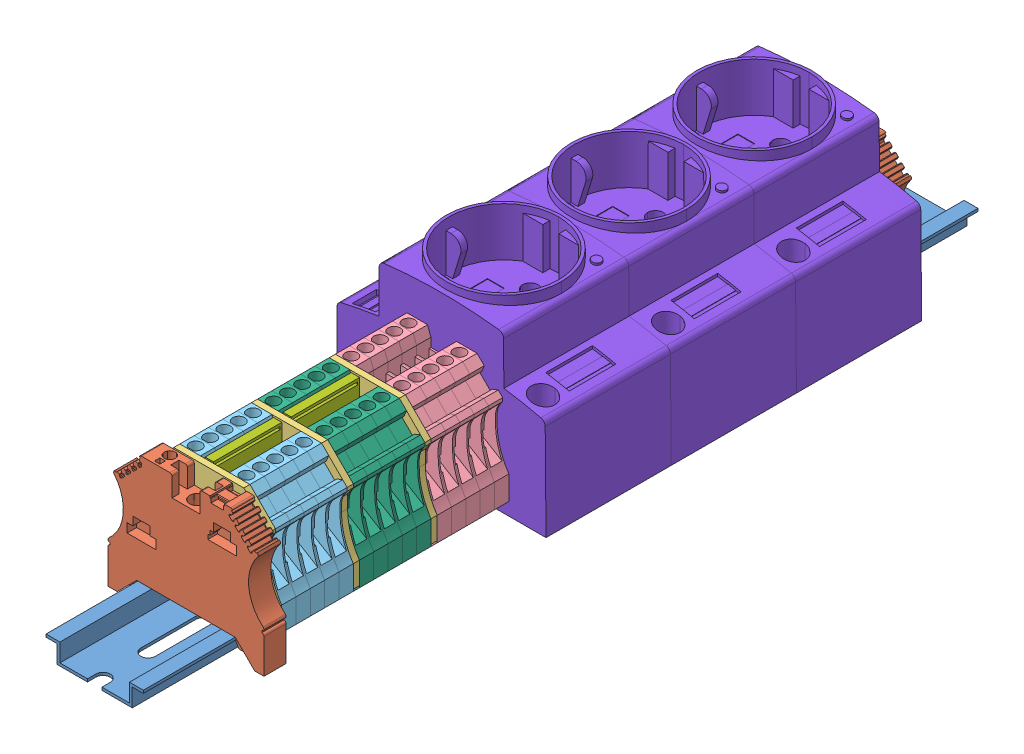
SolidWorks assembly 5xLNPE_Schuko, configuration Standard. Lengths in mm.
Overall size (75.48 67.56 300).
26 component instances, 8 part files, 78 mates.
Components (placement in the parent):
- Hutschiene-1: Hutschiene [300] at (-17.5 -7.5 -300) size (35 7.5 300)
- WEW_35_2-1: WEW_35_2 [Standard] at (-45.75 -7 -267.85) x (0 0 1) z (0 1 0) size (8 56.1 46.5)
- WEW_35_2-2: WEW_35_2 [Standard] at (10.35 -7 -33) x (0 0 -1) z (0 1 0) size (8 56.1 46.5)
- D_UT_2.5_10-1: D_UT_2.5_10 [Standard] at (-46.4297 58.45 -43.2) size (47 39.8 2.2)
- D_UT_2.5_10-2: D_UT_2.5_10 [Standard] at (-46.4297 58.45 -71.15) size (47 39.8 2.2)
- D_UT_2.5_10-3: D_UT_2.5_10 [Standard] at (-46.4297 58.45 -99.1) size (47 39.8 2.2)
- UT_2.5_PE-1: UT_2.5_PE [Standard] at (-48.6989 10.6178 -99.1) x (0.992546 -0.121869 0) z (0 0 1) size (49.27 50.96 5.15)
- UT_2.5_PE-2: UT_2.5_PE [Standard] at (-48.6989 10.6178 -104.25) x (0.992546 -0.121869 0) z (0 0 1) size (49.27 50.96 5.15)
- UT_2.5_PE-3: UT_2.5_PE [Standard] at (-48.6989 10.6178 -109.4) x (0.992546 -0.121869 0) z (0 0 1) size (49.27 50.96 5.15)
- UT_2.5_PE-4: UT_2.5_PE [Standard] at (-48.6989 10.6178 -114.55) x (0.992546 -0.121869 0) z (0 0 1) size (49.27 50.96 5.15)
- UT_2.5_PE-5: UT_2.5_PE [Standard] at (-48.6989 10.6178 -119.7) x (0.992546 -0.121869 0) z (0 0 1) size (49.27 50.96 5.15)
- UT_2.5-1: UT_2.5 [Standard] at (-48.6989 10.6178 -43.2) x (0.992546 -0.121869 0) z (0 0 1) size (49.27 50.96 5.15)
- UT_2.5-2: UT_2.5 [Standard] at (-48.6989 10.6178 -48.35) x (0.992546 -0.121869 0) z (0 0 1) size (49.27 50.96 5.15)
- UT_2.5-3: UT_2.5 [Standard] at (-48.6989 10.6178 -53.5) x (0.992546 -0.121869 0) z (0 0 1) size (49.27 50.96 5.15)
- UT_2.5-4: UT_2.5 [Standard] at (-48.6989 10.6178 -58.65) x (0.992546 -0.121869 0) z (0 0 1) size (49.27 50.96 5.15)
- UT_2.5-5: UT_2.5 [Standard] at (-48.6989 10.6178 -63.8) x (0.992546 -0.121869 0) z (0 0 1) size (49.27 50.96 5.15)
- UT_2.5_BU-1: UT_2.5_BU [Standard] at (-48.6989 10.6178 -71.15) x (0.992546 -0.121869 0) z (0 0 1) size (49.27 50.96 5.15)
- UT_2.5_BU-2: UT_2.5_BU [Standard] at (-48.6989 10.6178 -76.3) x (0.992546 -0.121869 0) z (0 0 1) size (49.27 50.96 5.15)
- UT_2.5_BU-3: UT_2.5_BU [Standard] at (-48.6989 10.6178 -81.45) x (0.992546 -0.121869 0) z (0 0 1) size (49.27 50.96 5.15)
- UT_2.5_BU-4: UT_2.5_BU [Standard] at (-48.6989 10.6178 -86.6) x (0.992546 -0.121869 0) z (0 0 1) size (49.27 50.96 5.15)
- UT_2.5_BU-5: UT_2.5_BU [Standard] at (-48.6989 10.6178 -91.75) x (0.992546 -0.121869 0) z (0 0 1) size (49.27 50.96 5.15)
- FBS_5_5-1: FBS_5_5 [Standard] at (-24.1072 48.875 -102.035) size (3 22.98 24.6)
- FBS_5_5-2: FBS_5_5 [Standard] at (-24.1072 48.875 -129.985) size (3 22.98 24.6)
- EO_CF_UT_LED-1: EO_CF_UT_LED [Standard] at (-87.0914 -21.0563 -149.6) size (75.48 61.64 45)
- EO_CF_UT_LED-2: EO_CF_UT_LED [Standard] at (-87.0914 -21.0563 -194.6) size (75.48 61.64 45)
- EO_CF_UT_LED-3: EO_CF_UT_LED [Standard] at (-87.0914 -21.0563 -239.6) size (75.48 61.64 45)
Mates (geometry in assembly coordinates):
- Deckungsgleich1: coincident aligned: plane of Hutschiene-1 through (-17.5 -7.5 0) normal (0 0 1); plane of assembly through (0 0 0) normal (0 0 1)
- Deckungsgleich2: coincident aligned: plane of Hutschiene-1 through (-30 0 0) normal (0 1 0); plane of assembly through (0 0 0) normal (0 1 0)
- Deckungsgleich3: coincident aligned: plane of Hutschiene-1 through (0 -1 0) normal (1 0 0); plane of assembly through (0 0 0) normal (1 0 0)
- Abstand1: distance = 33 mm aligned: plane of WEW_35_2-2 through (-17.7 0 -33) normal (0 0 1); plane of Hutschiene-1 through (-17.5 -7.5 0) normal (0 0 1)
- Deckungsgleich70: coincident anti-aligned: plane of Hutschiene-1 through (0 0 0) normal (0 1 0); plane of EO_CF_UT_LED-1 through (-54.05 0 -151.75) normal (0 -1 0)
- Deckungsgleich71: coincident anti-aligned: plane of Hutschiene-1 through (-30 0 0) normal (0 1 0); plane of EO_CF_UT_LED-2 through (-54.05 0 -196.75) normal (0 -1 0)
- Deckungsgleich72: coincident anti-aligned: plane of Hutschiene-1 through (-30 0 0) normal (0 1 0); plane of EO_CF_UT_LED-3 through (-54.05 0 -241.75) normal (0 -1 0)
- Deckungsgleich73: coincident anti-aligned: plane of Hutschiene-1 through (0 -1 0) normal (1 0 0); plane of EO_CF_UT_LED-1 through (0 8.9 -125.85) normal (-1 0 0)
- Deckungsgleich74: coincident anti-aligned: plane of Hutschiene-1 through (0 -1 0) normal (1 0 0); plane of EO_CF_UT_LED-2 through (0 8.9 -170.85) normal (-1 0 0)
- Deckungsgleich75: coincident anti-aligned: plane of Hutschiene-1 through (0 -1 0) normal (1 0 0); plane of EO_CF_UT_LED-3 through (0 8.9 -215.85) normal (-1 0 0)
- Deckungsgleich77: coincident anti-aligned: plane of EO_CF_UT_LED-1 through (-17.75 2.45 -169.85) normal (0 0 -1); plane of EO_CF_UT_LED-2 through (-17.75 2.45 -169.85) normal (0 0 1)
- Deckungsgleich78: coincident anti-aligned: plane of EO_CF_UT_LED-2 through (-17.75 2.45 -214.85) normal (0 0 -1); plane of EO_CF_UT_LED-3 through (-17.75 2.45 -214.85) normal (0 0 1)
- Deckungsgleich81: coincident anti-aligned: plane of Hutschiene-1 through (-30 0 0) normal (0 1 0); plane of WEW_35_2-2 through (-35.4 0 -41) normal (0 -1 0)
- Deckungsgleich82: coincident anti-aligned: plane of Hutschiene-1 through (-30 0 0) normal (0 1 0); plane of UT_2.5-1 through (-7.7 0 -43.2) normal (0 -1 0)
- Deckungsgleich83: coincident anti-aligned: plane of Hutschiene-1 through (-30 0 0) normal (0 1 0); plane of UT_2.5-2 through (-7.7 0 -48.35) normal (0 -1 0)
- Deckungsgleich84: coincident anti-aligned: plane of Hutschiene-1 through (-30 0 0) normal (0 1 0); plane of UT_2.5-3 through (-7.7 0 -53.5) normal (0 -1 0)
- Deckungsgleich85: coincident anti-aligned: plane of Hutschiene-1 through (-30 0 0) normal (0 1 0); plane of UT_2.5-4 through (-7.7 0 -58.65) normal (0 -1 0)
- Deckungsgleich86: coincident anti-aligned: plane of Hutschiene-1 through (-30 0 0) normal (0 1 0); plane of UT_2.5-5 through (-7.7 0 -63.8) normal (0 -1 0)
- Deckungsgleich87: coincident aligned: plane of D_UT_2.5_10-1 through (4.3 30.8 -42.1) normal (1 0 0); plane of UT_2.5-1 through (4.3 30.8 -43.2) normal (1 0 0)
- Deckungsgleich88: coincident aligned: line of D_UT_2.5_10-1 through (4.3 29.6 -43.2) axis (0 0 1); line of UT_2.5-1 through (4.3 29.6 -48.35) axis (0 0 1)
- Deckungsgleich89: coincident anti-aligned: plane of D_UT_2.5_10-1 through (8.926 -3.78 -43.2) normal (0 0 -1); plane of UT_2.5-1 through (0 0 -43.2) normal (0 0 1)
- Deckungsgleich90: coincident anti-aligned: plane of UT_2.5-1 through (0 0 -48.35) normal (0 0 -1); plane of UT_2.5-2 through (0 0 -48.35) normal (0 0 1)
- Deckungsgleich91: coincident anti-aligned: plane of UT_2.5-2 through (0 0 -53.5) normal (0 0 -1); plane of UT_2.5-3 through (0 0 -53.5) normal (0 0 1)
- Deckungsgleich92: coincident anti-aligned: plane of UT_2.5-3 through (0 0 -58.65) normal (0 0 -1); plane of UT_2.5-4 through (0 0 -58.65) normal (0 0 1)
- Deckungsgleich93: coincident anti-aligned: plane of UT_2.5-4 through (0 0 -63.8) normal (0 0 -1); plane of UT_2.5-5 through (0 0 -63.8) normal (0 0 1)
- Deckungsgleich94: coincident anti-aligned: plane of Hutschiene-1 through (0 -1 0) normal (1 0 0); plane of UT_2.5-1 through (0 -1.1 -43.2) normal (-1 0 0)
- Deckungsgleich95: coincident anti-aligned: plane of Hutschiene-1 through (0 -1 0) normal (1 0 0); plane of UT_2.5-2 through (0 -1.1 -48.35) normal (-1 0 0)
- Deckungsgleich96: coincident anti-aligned: plane of Hutschiene-1 through (0 -1 0) normal (1 0 0); plane of UT_2.5-3 through (0 -1.1 -53.5) normal (-1 0 0)
- Deckungsgleich97: coincident anti-aligned: plane of Hutschiene-1 through (0 -1 0) normal (1 0 0); plane of UT_2.5-4 through (0 -1.1 -58.65) normal (-1 0 0)
- Deckungsgleich98: coincident anti-aligned: plane of Hutschiene-1 through (0 -1 0) normal (1 0 0); plane of UT_2.5-5 through (0 -1.1 -63.8) normal (-1 0 0)
- Deckungsgleich99: coincident anti-aligned: plane of WEW_35_2-2 through (-17.7 0 -41) normal (0 0 -1); plane of D_UT_2.5_10-1 through (-31.3534 31.331 -41) normal (0 0 1)
- Deckungsgleich101: coincident: plane of Hutschiene-1 through (0 -1 0) normal (1 0 0); line of WEW_35_2-2 through (0 0 -41) axis (0 0 1)
- Deckungsgleich102: coincident anti-aligned: plane of UT_2.5-1 through (-18.35 21.85 -43.675) normal (0 0 -1); plane of FBS_5_5-1 through (-18.5 39.7 -43.675) normal (0 0 1)
- Deckungsgleich103: coincident anti-aligned: plane of UT_2.5-2 through (-21.5 36.703 -48.35) normal (1 0 0); plane of FBS_5_5-1 through (-21.5 38.7586 -57.6095) normal (-1 0 0)
- Deckungsgleich104: coincident aligned: plane of UT_2.5-1 through (-30.1 40 -43.2) normal (0 1 0); plane of FBS_5_5-1 through (-18.5 40 -54.075) normal (0 1 0)
- Deckungsgleich105: coincident anti-aligned: plane of D_UT_2.5_10-2 through (8.926 -3.78 -71.15) normal (0 0 -1); plane of UT_2.5_BU-1 through (0 0 -71.15) normal (0 0 1)
- Deckungsgleich106: coincident anti-aligned: plane of UT_2.5_BU-1 through (0 0 -76.3) normal (0 0 -1); plane of UT_2.5_BU-2 through (0 0 -76.3) normal (0 0 1)
- Deckungsgleich107: coincident anti-aligned: plane of UT_2.5_BU-2 through (0 0 -81.45) normal (0 0 -1); plane of UT_2.5_BU-3 through (0 0 -81.45) normal (0 0 1)
- Deckungsgleich108: coincident anti-aligned: plane of UT_2.5_BU-3 through (0 0 -86.6) normal (0 0 -1); plane of UT_2.5_BU-4 through (0 0 -86.6) normal (0 0 1)
- Deckungsgleich109: coincident anti-aligned: plane of UT_2.5_BU-4 through (0 0 -91.75) normal (0 0 -1); plane of UT_2.5_BU-5 through (0 0 -91.75) normal (0 0 1)
- Deckungsgleich110: coincident anti-aligned: plane of Hutschiene-1 through (-30 0 0) normal (0 1 0); plane of UT_2.5_BU-1 through (-7.7 0 -71.15) normal (0 -1 0)
- Deckungsgleich111: coincident anti-aligned: plane of Hutschiene-1 through (-30 0 0) normal (0 1 0); plane of UT_2.5_BU-2 through (-7.7 0 -76.3) normal (0 -1 0)
- Deckungsgleich112: coincident anti-aligned: plane of Hutschiene-1 through (-30 0 0) normal (0 1 0); plane of UT_2.5_BU-3 through (-7.7 0 -81.45) normal (0 -1 0)
- Deckungsgleich113: coincident anti-aligned: plane of Hutschiene-1 through (-30 0 0) normal (0 1 0); plane of UT_2.5_BU-4 through (-7.7 0 -86.6) normal (0 -1 0)
- Deckungsgleich114: coincident anti-aligned: plane of Hutschiene-1 through (-30 0 0) normal (0 1 0); plane of UT_2.5_BU-5 through (-7.7 0 -91.75) normal (0 -1 0)
- Deckungsgleich115: coincident aligned: plane of D_UT_2.5_10-2 through (4.3 30.8 -70.05) normal (1 0 0); plane of UT_2.5_BU-1 through (4.3 30.8 -71.15) normal (1 0 0)
- Deckungsgleich116: coincident aligned: line of D_UT_2.5_10-2 through (4.3 29.6 -71.15) axis (0 0 1); line of UT_2.5_BU-1 through (4.3 29.6 -76.3) axis (0 0 1)
- Deckungsgleich117: coincident anti-aligned: plane of Hutschiene-1 through (0 -1 0) normal (1 0 0); plane of UT_2.5_BU-1 through (0 -1.1 -71.15) normal (-1 0 0)
- Deckungsgleich118: coincident anti-aligned: plane of Hutschiene-1 through (0 -1 0) normal (1 0 0); plane of UT_2.5_BU-2 through (0 -1.1 -76.3) normal (-1 0 0)
- Deckungsgleich119: coincident anti-aligned: plane of Hutschiene-1 through (0 -1 0) normal (1 0 0); plane of UT_2.5_BU-3 through (0 -1.1 -81.45) normal (-1 0 0)
- Deckungsgleich120: coincident anti-aligned: plane of Hutschiene-1 through (0 -1 0) normal (1 0 0); plane of UT_2.5_BU-4 through (0 -1.1 -86.6) normal (-1 0 0)
- Deckungsgleich121: coincident anti-aligned: plane of Hutschiene-1 through (0 -1 0) normal (1 0 0); plane of UT_2.5_BU-5 through (0 -1.1 -91.75) normal (-1 0 0)
- Deckungsgleich122: coincident anti-aligned: plane of D_UT_2.5_10-2 through (-31.3534 31.331 -68.95) normal (0 0 1); plane of UT_2.5-5 through (0 0 -68.95) normal (0 0 -1)
- Deckungsgleich123: coincident anti-aligned: plane of UT_2.5_BU-1 through (-18.35 21.85 -71.625) normal (0 0 -1); plane of FBS_5_5-2 through (-18.5 39.7 -71.625) normal (0 0 1)
- Deckungsgleich124: coincident anti-aligned: plane of UT_2.5_BU-1 through (-21.5 36.703 -71.15) normal (1 0 0); plane of FBS_5_5-2 through (-21.5 38.7586 -85.5595) normal (-1 0 0)
- Deckungsgleich125: coincident aligned: plane of UT_2.5_BU-1 through (-30.1 40 -71.15) normal (0 1 0); plane of FBS_5_5-2 through (-18.5 40 -82.025) normal (0 1 0)
- Deckungsgleich126: coincident anti-aligned: plane of D_UT_2.5_10-3 through (8.926 -3.78 -99.1) normal (0 0 -1); plane of UT_2.5_PE-1 through (0 0 -99.1) normal (0 0 1)
- Deckungsgleich127: coincident anti-aligned: plane of UT_2.5_PE-1 through (0 0 -104.25) normal (0 0 -1); plane of UT_2.5_PE-2 through (0 0 -104.25) normal (0 0 1)
- Deckungsgleich128: coincident anti-aligned: plane of UT_2.5_PE-2 through (0 0 -109.4) normal (0 0 -1); plane of UT_2.5_PE-3 through (0 0 -109.4) normal (0 0 1)
- Deckungsgleich129: coincident anti-aligned: plane of UT_2.5_PE-3 through (0 0 -114.55) normal (0 0 -1); plane of UT_2.5_PE-4 through (0 0 -114.55) normal (0 0 1)
- Deckungsgleich130: coincident anti-aligned: plane of UT_2.5_PE-4 through (0 0 -119.7) normal (0 0 -1); plane of UT_2.5_PE-5 through (0 0 -119.7) normal (0 0 1)
- Deckungsgleich131: coincident aligned: plane of D_UT_2.5_10-3 through (4.3 30.8 -98) normal (1 0 0); plane of UT_2.5_PE-1 through (4.3 30.8 -99.1) normal (1 0 0)
- Deckungsgleich132: coincident aligned: line of D_UT_2.5_10-3 through (4.3 30.8 -99.1) axis (0 0 1); line of UT_2.5_PE-1 through (4.3 30.8 -104.25) axis (0 0 1)
- Deckungsgleich133: coincident anti-aligned: plane of Hutschiene-1 through (-30 0 0) normal (0 1 0); plane of UT_2.5_PE-5 through (-7.7 0 -119.7) normal (0 -1 0)
- Deckungsgleich134: coincident anti-aligned: plane of Hutschiene-1 through (-30 0 0) normal (0 1 0); plane of UT_2.5_PE-4 through (-7.7 0 -114.55) normal (0 -1 0)
- Deckungsgleich135: coincident anti-aligned: plane of Hutschiene-1 through (-30 0 0) normal (0 1 0); plane of UT_2.5_PE-3 through (-7.7 0 -109.4) normal (0 -1 0)
- Deckungsgleich136: coincident anti-aligned: plane of Hutschiene-1 through (-30 0 0) normal (0 1 0); plane of UT_2.5_PE-2 through (-7.7 0 -104.25) normal (0 -1 0)
- Deckungsgleich137: coincident anti-aligned: plane of Hutschiene-1 through (-30 0 0) normal (0 1 0); plane of UT_2.5_PE-1 through (-7.7 0 -99.1) normal (0 -1 0)
- Deckungsgleich138: coincident anti-aligned: plane of Hutschiene-1 through (0 -1 0) normal (1 0 0); plane of UT_2.5_PE-1 through (0 -1.1 -99.1) normal (-1 0 0)
- Deckungsgleich139: coincident anti-aligned: plane of Hutschiene-1 through (0 -1 0) normal (1 0 0); plane of UT_2.5_PE-2 through (0 -1.1 -104.25) normal (-1 0 0)
- Deckungsgleich140: coincident anti-aligned: plane of Hutschiene-1 through (0 -1 0) normal (1 0 0); plane of UT_2.5_PE-3 through (0 -1.1 -109.4) normal (-1 0 0)
- Deckungsgleich141: coincident anti-aligned: plane of Hutschiene-1 through (0 -1 0) normal (1 0 0); plane of UT_2.5_PE-4 through (0 -1.1 -114.55) normal (-1 0 0)
- Deckungsgleich142: coincident anti-aligned: plane of Hutschiene-1 through (0 -1 0) normal (1 0 0); plane of UT_2.5_PE-5 through (0 -1.1 -119.7) normal (-1 0 0)
- Deckungsgleich143: coincident anti-aligned: plane of D_UT_2.5_10-3 through (-31.3534 31.331 -96.9) normal (0 0 1); plane of UT_2.5_BU-5 through (0 0 -96.9) normal (0 0 -1)
- Deckungsgleich144: coincident anti-aligned: plane of UT_2.5_PE-5 through (0 0 -124.85) normal (0 0 -1); plane of EO_CF_UT_LED-1 through (-17.75 2.45 -124.85) normal (0 0 1)
- Deckungsgleich145: coincident anti-aligned: plane of WEW_35_2-1 through (-17.7 0 -259.85) normal (0 0 1); plane of EO_CF_UT_LED-3 through (-17.75 2.45 -259.85) normal (0 0 -1)
- Deckungsgleich146: coincident anti-aligned: plane of Hutschiene-1 through (0 0 0) normal (0 1 0); plane of WEW_35_2-1 through (0 0 -259.85) normal (0 -1 0)
- Deckungsgleich147: coincident anti-aligned: line of Hutschiene-1 through (0 0 0) axis (0 0 -1); line of WEW_35_2-1 through (0 0 -267.85) axis (0 0 1)
